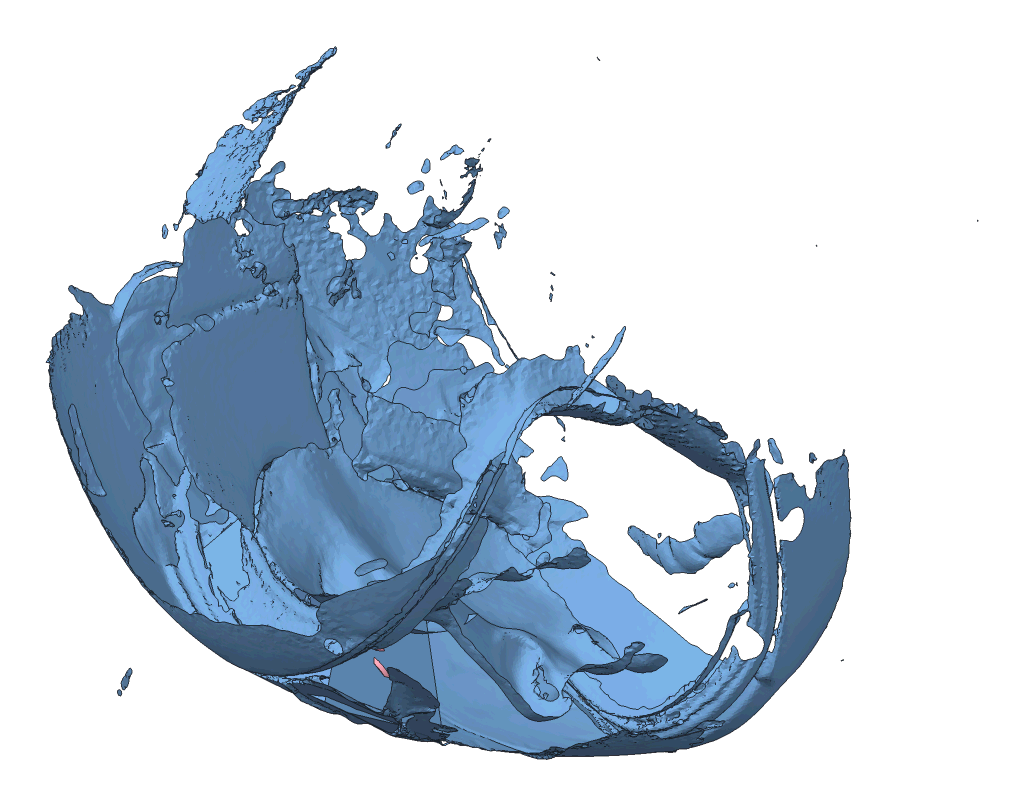
SolidWorks assembly asm, configuration По умолчанию. Lengths in mm.
Overall size (270.91 239.79 235.47).
5 component instances, 4 part files, 2 mates.
Components (placement in the parent):
- _helmet with face v3-1: _helmet with face v3 [По умолчанию] at origin size (270.91 239.79 235.47)
- _okular-1: _okular [По умолчанию] at (-500.6053 890.0701 4091.668) x (0.961022 0.266183 0.074727) z (0.012036 0.22975 -0.973175) size (39 20 18.3)
  - _lensHolder-1: _lensHolder [По умолчанию] at origin size (29.5 16.75 9.4)
  - _display-1: _display [По умолчанию] at (0.075 0.225 -5.75) size (14.55 16.9 4)
  - _cover-1: _cover [По умолчанию] at (-0.2 -0.075 7.35) x (1 0 0) z (0 0 -1) size (39 20 7.2)
Mates (geometry in assembly coordinates):
- Расстояние1: distance = 25 mm: point of okular-1/cover-1; point of helmet with face v3-1
- Совпадение3: coincident: unknown of okular-1/cover-1
